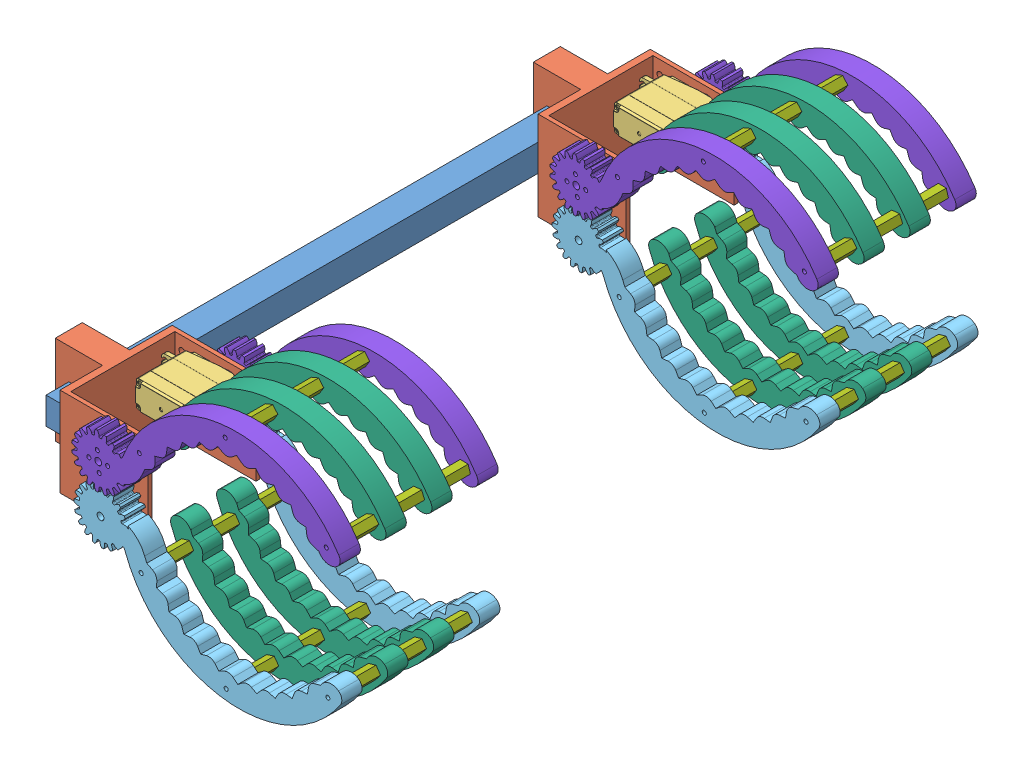
SolidWorks assembly 装配体_整, configuration Default. Lengths in mm.
Overall size (261.78 194.91 472.45).
65 component instances, 8 part files, 6 mates.
Components (placement in the parent):
- 6.横杆的简易模型-1: 6.横杆的简易模型 [默认] at origin size (20 20 400)
- 装配体_爪子加舵机-1: 装配体_爪子加舵机 [Default] at (2.5929 19.9341 -22.1435) size (261.78 194.91 118.7)
  - 3.固定舵机盘-1: 3.固定舵机盘 [默认] at origin size (100 66 87)
  - 4.35KGservo-1: 4.35KGservo [默认] at (35.5165 11.5325 23.201) x (1 0 0) z (0 1 0) size (62.21 45.03 20.04)
  - 5.舵机圆形头-1: 5.舵机圆形头 [默认] at (35.5165 11.5325 23.6787) x (1 0 0) z (0 1 0) size (19.5 4.4 19.5)
  - 装配体_右爪子-1: 装配体_右爪子 [Default] at (137.7363 -24.1002 -6.499) x (0.117021 0.993129 0) z (0 0 -1) size (79.93 200.48 117)
    - 1_2.右爪子表面_打印两个-1: 1_2.右爪子表面_打印两个 [Varsayılan] at origin size (79.93 200.48 15)
    - 1_3.爪子中间_打印四个-1: 1_3.爪子中间_打印四个 [Varsayılan] at (-2.9763 8.2953 -34) size (58.35 161.77 15)
    - 2.铜柱连接件-1: 2.铜柱连接件 [Varsayılan] at (-63.7872 8.2778 -21.5) size (9.37 9.17 19)
    - 2.铜柱连接件-2: 2.铜柱连接件 [Varsayılan] at (-23.2882 79.2861 -21.5) size (9.37 9.17 19)
    - 2.铜柱连接件-3: 2.铜柱连接件 [Varsayılan] at (-23.2882 79.2861 -55.5) size (9.37 9.17 19)
    - 2.铜柱连接件-4: 2.铜柱连接件 [Varsayılan] at (-28.7173 -59.225 -21.5) size (9.37 9.17 19)
    - 2.铜柱连接件-5: 2.铜柱连接件 [Varsayılan] at (-28.7173 -59.225 -55.5) size (9.37 9.17 19)
    - 2.铜柱连接件-6: 2.铜柱连接件 [Varsayılan] at (-23.2882 79.2861 -89.5) size (9.37 9.17 19)
    - 2.铜柱连接件-7: 2.铜柱连接件 [Varsayılan] at (-28.7173 -59.225 -89.5) size (9.37 9.17 19)
    - 2.铜柱连接件-8: 2.铜柱连接件 [Varsayılan] at (-63.7872 8.2778 -55.5) size (9.37 9.17 19)
    - 2.铜柱连接件-9: 2.铜柱连接件 [Varsayılan] at (-63.7872 8.2778 -70.5) x (-0.498458 -0.866914 0) z (0 0 -1) size (9.37 9.17 19)
    - 1_3.爪子中间_打印四个-2: 1_3.爪子中间_打印四个 [Varsayılan] at (-2.9763 8.2953 -68) size (58.35 161.77 15)
    - 1_2.右爪子表面_打印两个-2: 1_2.右爪子表面_打印两个 [Varsayılan] at (0 0 -102) size (79.93 200.48 15)
  - 装配体_左爪子-1: 装配体_左爪子 [Default] at (137.8802 9.6724 87.201) x (0.101561 -0.994829 0) z (0 0 1) size (79.66 200.49 117)
    - 1_1.左爪子表面_打印两个-1: 1_1.左爪子表面_打印两个 [Varsayılan] at origin size (79.66 200.49 15)
    - 1_3.爪子中间_打印四个-1: 1_3.爪子中间_打印四个 [Varsayılan] at (-2.9202 8.1355 -34) size (58.35 161.77 15)
    - 2.铜柱连接件-1: 2.铜柱连接件 [Varsayılan] at (-28.6612 -59.3847 -21.5) x (0.366858 -0.930277 0) z (0 0 1) size (9.37 9.17 19)
    - 2.铜柱连接件-2: 2.铜柱连接件 [Varsayılan] at (-63.7311 8.1181 -21.5) x (0.366858 -0.930277 0) z (0 0 1) size (9.37 9.17 19)
    - 2.铜柱连接件-3: 2.铜柱连接件 [Varsayılan] at (-23.232 79.1263 -21.5) x (0.366858 -0.930277 0) z (0 0 1) size (9.37 9.17 19)
    - 2.铜柱连接件-4: 2.铜柱连接件 [Varsayılan] at (-23.232 79.1263 -55.5) x (-0.923835 -0.38279 0) z (0 0 1) size (9.37 9.17 19)
    - 2.铜柱连接件-5: 2.铜柱连接件 [Varsayılan] at (-63.7311 8.1181 -55.5) x (0.366858 -0.930277 0) z (0 0 1) size (9.37 9.17 19)
    - 2.铜柱连接件-6: 2.铜柱连接件 [Varsayılan] at (-28.6612 -59.3847 -55.5) x (0.366858 -0.930277 0) z (0 0 1) size (9.37 9.17 19)
    - 2.铜柱连接件-7: 2.铜柱连接件 [Varsayılan] at (-28.6612 -59.3847 -89.5) x (0.366858 -0.930277 0) z (0 0 1) size (9.37 9.17 19)
    - 2.铜柱连接件-8: 2.铜柱连接件 [Varsayılan] at (-23.232 79.1263 -89.5) x (-0.960896 -0.276909 0) z (0 0 1) size (9.37 9.17 19)
    - 2.铜柱连接件-9: 2.铜柱连接件 [Varsayılan] at (-63.7311 8.1181 -89.5) x (0.366858 -0.930277 0) z (0 0 1) size (9.37 9.17 19)
    - 1_3.爪子中间_打印四个-2: 1_3.爪子中间_打印四个 [Varsayılan] at (-2.9202 8.1355 -68) size (58.35 161.77 15)
    - 1_1.左爪子表面_打印两个-2: 1_1.左爪子表面_打印两个 [Varsayılan] at (0 0 -102) size (79.66 200.49 15)
- 装配体_爪子加舵机-2: 装配体_爪子加舵机 [Default] at (2.5929 19.9341 331.603) size (261.78 194.91 118.7)
  - 3.固定舵机盘-1: 3.固定舵机盘 [默认] at origin size (100 66 87)
  - 4.35KGservo-1: 4.35KGservo [默认] at (35.5165 11.5325 23.201) x (1 0 0) z (0 1 0) size (62.21 45.03 20.04)
  - 5.舵机圆形头-1: 5.舵机圆形头 [默认] at (35.5165 11.5325 23.6787) x (1 0 0) z (0 1 0) size (19.5 4.4 19.5)
  - 装配体_右爪子-1: 装配体_右爪子 [Default] at (137.7363 -24.1002 -6.499) x (0.117021 0.993129 0) z (0 0 -1) size (79.93 200.48 117)
    - 1_2.右爪子表面_打印两个-1: 1_2.右爪子表面_打印两个 [Varsayılan] at origin size (79.93 200.48 15)
    - 1_3.爪子中间_打印四个-1: 1_3.爪子中间_打印四个 [Varsayılan] at (-2.9763 8.2953 -34) size (58.35 161.77 15)
    - 2.铜柱连接件-1: 2.铜柱连接件 [Varsayılan] at (-63.7872 8.2778 -21.5) size (9.37 9.17 19)
    - 2.铜柱连接件-2: 2.铜柱连接件 [Varsayılan] at (-23.2882 79.2861 -21.5) size (9.37 9.17 19)
    - 2.铜柱连接件-3: 2.铜柱连接件 [Varsayılan] at (-23.2882 79.2861 -55.5) size (9.37 9.17 19)
    - 2.铜柱连接件-4: 2.铜柱连接件 [Varsayılan] at (-28.7173 -59.225 -21.5) size (9.37 9.17 19)
    - 2.铜柱连接件-5: 2.铜柱连接件 [Varsayılan] at (-28.7173 -59.225 -55.5) size (9.37 9.17 19)
    - 2.铜柱连接件-6: 2.铜柱连接件 [Varsayılan] at (-23.2882 79.2861 -89.5) size (9.37 9.17 19)
    - 2.铜柱连接件-7: 2.铜柱连接件 [Varsayılan] at (-28.7173 -59.225 -89.5) size (9.37 9.17 19)
    - 2.铜柱连接件-8: 2.铜柱连接件 [Varsayılan] at (-63.7872 8.2778 -55.5) size (9.37 9.17 19)
    - 2.铜柱连接件-9: 2.铜柱连接件 [Varsayılan] at (-63.7872 8.2778 -70.5) x (-0.498458 -0.866914 0) z (0 0 -1) size (9.37 9.17 19)
    - 1_3.爪子中间_打印四个-2: 1_3.爪子中间_打印四个 [Varsayılan] at (-2.9763 8.2953 -68) size (58.35 161.77 15)
    - 1_2.右爪子表面_打印两个-2: 1_2.右爪子表面_打印两个 [Varsayılan] at (0 0 -102) size (79.93 200.48 15)
  - 装配体_左爪子-1: 装配体_左爪子 [Default] at (137.8802 9.6724 87.201) x (0.101561 -0.994829 0) z (0 0 1) size (79.66 200.49 117)
    - 1_1.左爪子表面_打印两个-1: 1_1.左爪子表面_打印两个 [Varsayılan] at origin size (79.66 200.49 15)
    - 1_3.爪子中间_打印四个-1: 1_3.爪子中间_打印四个 [Varsayılan] at (-2.9202 8.1355 -34) size (58.35 161.77 15)
    - 2.铜柱连接件-1: 2.铜柱连接件 [Varsayılan] at (-28.6612 -59.3847 -21.5) x (0.366858 -0.930277 0) z (0 0 1) size (9.37 9.17 19)
    - 2.铜柱连接件-2: 2.铜柱连接件 [Varsayılan] at (-63.7311 8.1181 -21.5) x (0.366858 -0.930277 0) z (0 0 1) size (9.37 9.17 19)
    - 2.铜柱连接件-3: 2.铜柱连接件 [Varsayılan] at (-23.232 79.1263 -21.5) x (0.366858 -0.930277 0) z (0 0 1) size (9.37 9.17 19)
    - 2.铜柱连接件-4: 2.铜柱连接件 [Varsayılan] at (-23.232 79.1263 -55.5) x (-0.923835 -0.38279 0) z (0 0 1) size (9.37 9.17 19)
    - 2.铜柱连接件-5: 2.铜柱连接件 [Varsayılan] at (-63.7311 8.1181 -55.5) x (0.366858 -0.930277 0) z (0 0 1) size (9.37 9.17 19)
    - 2.铜柱连接件-6: 2.铜柱连接件 [Varsayılan] at (-28.6612 -59.3847 -55.5) x (0.366858 -0.930277 0) z (0 0 1) size (9.37 9.17 19)
    - 2.铜柱连接件-7: 2.铜柱连接件 [Varsayılan] at (-28.6612 -59.3847 -89.5) x (0.366858 -0.930277 0) z (0 0 1) size (9.37 9.17 19)
    - 2.铜柱连接件-8: 2.铜柱连接件 [Varsayılan] at (-23.232 79.1263 -89.5) x (-0.960896 -0.276909 0) z (0 0 1) size (9.37 9.17 19)
    - 2.铜柱连接件-9: 2.铜柱连接件 [Varsayılan] at (-63.7311 8.1181 -89.5) x (0.366858 -0.930277 0) z (0 0 1) size (9.37 9.17 19)
    - 1_3.爪子中间_打印四个-2: 1_3.爪子中间_打印四个 [Varsayılan] at (-2.9202 8.1355 -68) size (58.35 161.77 15)
    - 1_1.左爪子表面_打印两个-2: 1_1.左爪子表面_打印两个 [Varsayılan] at (0 0 -102) size (79.66 200.49 15)
Mates (geometry in assembly coordinates):
- 重合1: coincident anti-aligned: plane of 6.横杆的简易模型-1 through (-21.8405 23.4666 400) normal (0 1 0); plane of 装配体_爪子加舵机-1/3.固定舵机盘-1 through (-1.8405 23.4666 77.8575) normal (0 -1 0)
- 重合2: coincident anti-aligned: plane of 6.横杆的简易模型-1 through (-21.8405 23.4666 400) normal (-1 0 0); plane of 装配体_爪子加舵机-1/3.固定舵机盘-1 through (-21.8405 23.4666 77.8575) normal (1 0 0)
- 锁定1: lock: unknown of 6.横杆的简易模型-1; unknown of 装配体_爪子加舵机-1/3.固定舵机盘-1
- 重合4: coincident anti-aligned: plane of 6.横杆的简易模型-1 through (-21.8405 23.4666 400) normal (-1 0 0); plane of 装配体_爪子加舵机-2/3.固定舵机盘-1 through (-21.8405 23.4666 431.604) normal (1 0 0)
- 重合5: coincident anti-aligned: plane of 6.横杆的简易模型-1 through (-21.8405 23.4666 400) normal (0 1 0); plane of 装配体_爪子加舵机-2/3.固定舵机盘-1 through (-1.8405 23.4666 431.604) normal (0 -1 0)
- 锁定2: lock: unknown of 6.横杆的简易模型-1; unknown of 装配体_爪子加舵机-2/3.固定舵机盘-1
